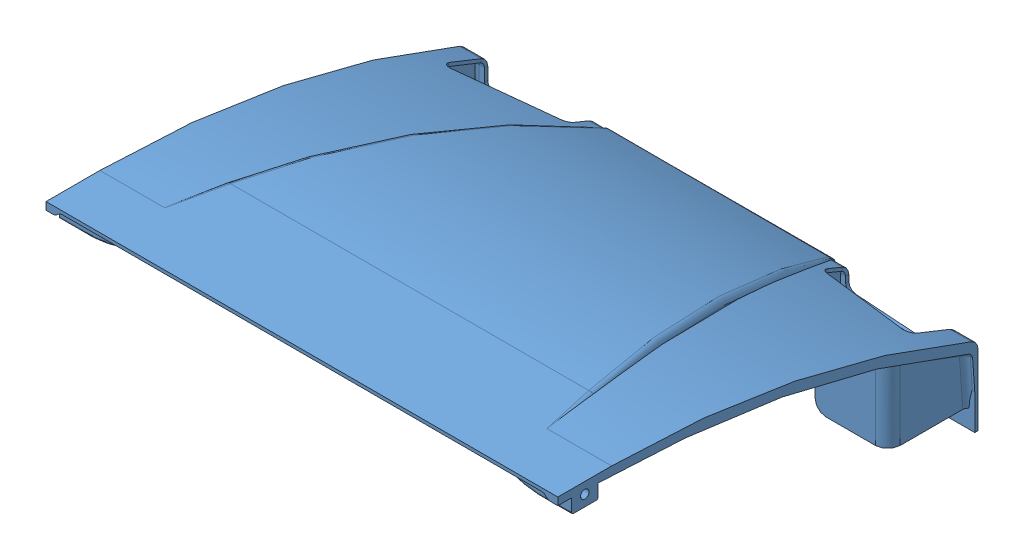
SolidWorks assembly CHASSIS, HOOD, 3D Print, configuration Default. Lengths in mm.
Overall size (120.65 35.99 101.85).
2 component instances, 2 part files, 3 mates.
Components (placement in the parent):
- CHASSIS, PLATE, HOOD-1: CHASSIS, PLATE, HOOD [3D Printed] at (-96.1662 -11.8437 58.792) size (120.65 35.99 99.63)
- CHASSIS, HOOD, SENSOR MOUNT-1: CHASSIS, HOOD, SENSOR MOUNT [Default] at (-96.1662 -0.4772 -39.506) size (50.8 16.13 8.89)
Mates (geometry in assembly coordinates):
- Coincident1: coincident anti-aligned: plane of CHASSIS, PLATE, HOOD-1 through (-35.8412 -11.8437 -39.506) normal (0 0 1); plane of CHASSIS, HOOD, SENSOR MOUNT-1 through (-70.7662 7.5873 -39.506) normal (0 0 -1)
- Concentric1: concentric anti-aligned: cylinder of CHASSIS, PLATE, HOOD-1 through (-96.1662 -5.4937 -40.8379) axis (0 0 1) radius 1.2192; cylinder of CHASSIS, HOOD, SENSOR MOUNT-1 through (-96.1662 -5.4937 -39.506) axis (0 0 -1) radius 1.0922
- Parallel1: parallel aligned: plane of CHASSIS, PLATE, HOOD-1 through (-35.8412 -11.0817 -39.506) normal (0 -1 0); plane of CHASSIS, HOOD, SENSOR MOUNT-1 through (-121.5662 -8.5417 -34.172) normal (0 -1 0)
